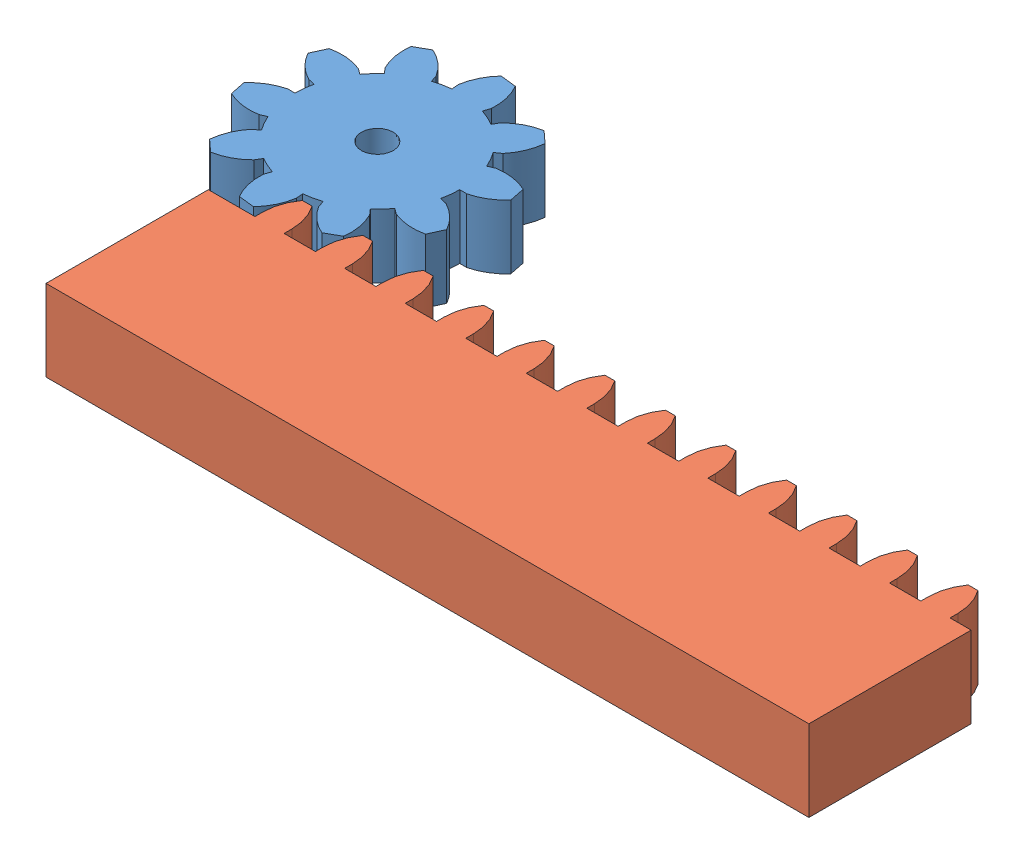
SolidWorks assembly MS-A-0017-Rack And Pinion Proto, configuration Default. Lengths in mm.
Overall size (134.65 12.7 67.25).
2 component instances, 2 part files, 7 mates.
Components (placement in the parent):
- MS-P-0058-Release Mech Spur Gear-1: MS-P-0058-Release Mech Spur Gear [Default] at (0 -10 0) x (0.215572 0 -0.976488) z (0.976488 0 0.215572) size (37.1 10 36.76)
- MS-P-0059-Rack-1: MS-P-0059-Rack [Default] at (53.0107 -12.7 32.472) size (119.38 12.7 31.3)
Mates (geometry in assembly coordinates):
- Coincident5: coincident aligned: plane of gear cool stupid long way-1 through (0 0 0) normal (0 1 0); plane of Rack-1 through (53.0107 0 32.472) normal (0 1 0)
- Concentric5: concentric anti-aligned: cylinder of gear cool stupid long way-1 through (0 0 0) axis (0 -1 0) radius 2.5
- Coincident9: coincident aligned: plane of gear cool stupid long way-1 through (0 0 0) normal (0 1 0)
- Coincident13: coincident aligned: plane of gear cool stupid long way-1 through (0 0 0) normal (0 1 0); plane of Rack-1 through (53.0107 0 32.472) normal (0 1 0)
- Parallel2: parallel aligned: plane of Rack-1 through (53.0107 0 45.172) normal (0 0 1)
- RackPinionMate1: rack pinion = 30 mm: line of Rack-1 through (-6.6793 0 45.172) axis (1 0 0); circle of gear cool stupid long way-1
- Distance1: distance = 42.672 mm: cylinder of gear cool stupid long way-1 through (0 0 0) axis (0 -1 0) radius 2.5; line of Rack-1 through (-6.6793 0 45.172) axis (1 0 0)
